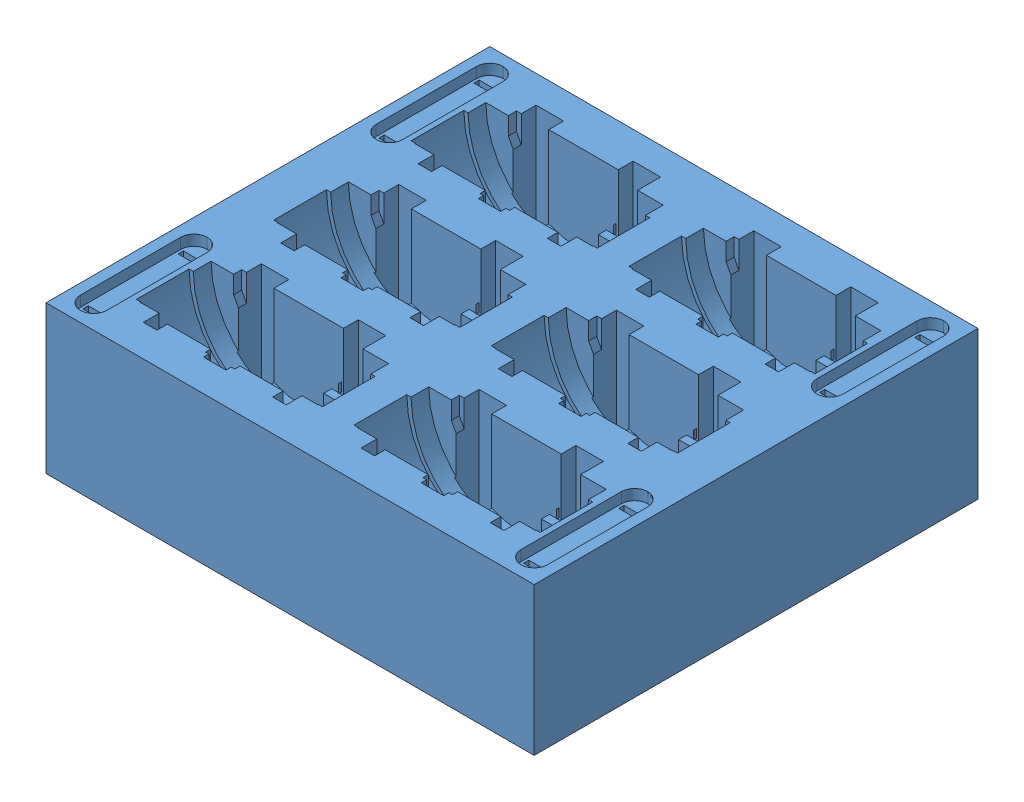
SolidWorks assembly Foam assy temp, configuration Default. Lengths in mm.
Overall size (293.37 88.9 266.7).
31 component instances, 5 part files, 3 mates.
Components (placement in the parent):
- foam with zipties-1: foam with zipties [Default] at (25.9363 149.1789 323.0178) size (293.37 88.9 266.7)
- toastModel-1: toastModel [Default] at (-24.201 119.3871 213.0318) x (-1 0 0) z (0 -1 0) size (111.76 62.87 55.88) (hidden)
  - toastBig-1: toastBig [Default] at (0.4326 -0.2782 -0.0393) size (111.76 32 55.88)
  - toastSmall-1: toastSmall [Default] at (0.4326 42.3938 -0.0393) size (106.68 10.67 53.34)
  - toastTop-1: toastTop [Default] at (7.1767 -15.6078 -0.0393) x (-1 0 0) z (0 0 1) size (76.71 10.67 53.07)
  - toastBottom-1: toastBottom [Default] at (5.9748 -12.4328 -0.0393) x (-1 0 0) z (0 0 1) size (85.85 9.53 45.09)
- toastModel-2: toastModel [Default] at (-24.201 119.3871 295.5818) x (-1 0 0) z (0 -1 0) size (111.76 62.87 55.88) (hidden)
  - toastBig-1: toastBig [Default] at (0.4326 -0.2782 -0.0393) size (111.76 32 55.88)
  - toastSmall-1: toastSmall [Default] at (0.4326 42.3938 -0.0393) size (106.68 10.67 53.34)
  - toastTop-1: toastTop [Default] at (7.1767 -15.6078 -0.0393) x (-1 0 0) z (0 0 1) size (76.71 10.67 53.07)
  - toastBottom-1: toastBottom [Default] at (5.9748 -12.4328 -0.0393) x (-1 0 0) z (0 0 1) size (85.85 9.53 45.09)
- toastModel-3: toastModel [Default] at (-24.201 119.3871 378.1318) x (-1 0 0) z (0 -1 0) size (111.76 62.87 55.88) (hidden)
  - toastBig-1: toastBig [Default] at (0.4326 -0.2782 -0.0393) size (111.76 32 55.88)
  - toastSmall-1: toastSmall [Default] at (0.4326 42.3938 -0.0393) size (106.68 10.67 53.34)
  - toastTop-1: toastTop [Default] at (7.1767 -15.6078 -0.0393) x (-1 0 0) z (0 0 1) size (76.71 10.67 53.07)
  - toastBottom-1: toastBottom [Default] at (5.9748 -12.4328 -0.0393) x (-1 0 0) z (0 0 1) size (85.85 9.53 45.09)
- toastModel-4: toastModel [Default] at (106.609 119.3871 213.0318) x (-1 0 0) z (0 -1 0) size (111.76 62.87 55.88) (hidden)
  - toastBig-1: toastBig [Default] at (0.4326 -0.2782 -0.0393) size (111.76 32 55.88)
  - toastSmall-1: toastSmall [Default] at (0.4326 42.3938 -0.0393) size (106.68 10.67 53.34)
  - toastTop-1: toastTop [Default] at (7.1767 -15.6078 -0.0393) x (-1 0 0) z (0 0 1) size (76.71 10.67 53.07)
  - toastBottom-1: toastBottom [Default] at (5.9748 -12.4328 -0.0393) x (-1 0 0) z (0 0 1) size (85.85 9.53 45.09)
- toastModel-5: toastModel [Default] at (106.609 119.3871 295.5818) x (-1 0 0) z (0 -1 0) size (111.76 62.87 55.88) (hidden)
  - toastBig-1: toastBig [Default] at (0.4326 -0.2782 -0.0393) size (111.76 32 55.88)
  - toastSmall-1: toastSmall [Default] at (0.4326 42.3938 -0.0393) size (106.68 10.67 53.34)
  - toastTop-1: toastTop [Default] at (7.1767 -15.6078 -0.0393) x (-1 0 0) z (0 0 1) size (76.71 10.67 53.07)
  - toastBottom-1: toastBottom [Default] at (5.9748 -12.4328 -0.0393) x (-1 0 0) z (0 0 1) size (85.85 9.53 45.09)
- toastModel-6: toastModel [Default] at (106.609 119.3871 378.1318) x (-1 0 0) z (0 -1 0) size (111.76 62.87 55.88) (hidden)
  - toastBig-1: toastBig [Default] at (0.4326 -0.2782 -0.0393) size (111.76 32 55.88)
  - toastSmall-1: toastSmall [Default] at (0.4326 42.3938 -0.0393) size (106.68 10.67 53.34)
  - toastTop-1: toastTop [Default] at (7.1767 -15.6078 -0.0393) x (-1 0 0) z (0 0 1) size (76.71 10.67 53.07)
  - toastBottom-1: toastBottom [Default] at (5.9748 -12.4328 -0.0393) x (-1 0 0) z (0 0 1) size (85.85 9.53 45.09)
Mates (geometry in assembly coordinates):
- Coincident1: coincident aligned: plane of foam with zipties-1 through (25.9363 149.1789 323.0178) normal (0 1 0); plane of toastModel-1/toastBig-1 through (-83.8251 149.1789 257.246) normal (0 1 0)
- Coincident2: coincident anti-aligned: line of foam with zipties-1 through (-83.8251 149.1789 244.9143) axis (1 0 0); line of toastModel-1/toastBottom-1 through (-20.1377 149.1789 244.9143) axis (-1 0 0)
- Coincident3: coincident anti-aligned: line of foam with zipties-1 through (27.9349 149.1789 244.9143) axis (0 0 -1); line of toastModel-1/toastBig-1 through (27.9349 149.1789 203.3853) axis (0 0 1)
